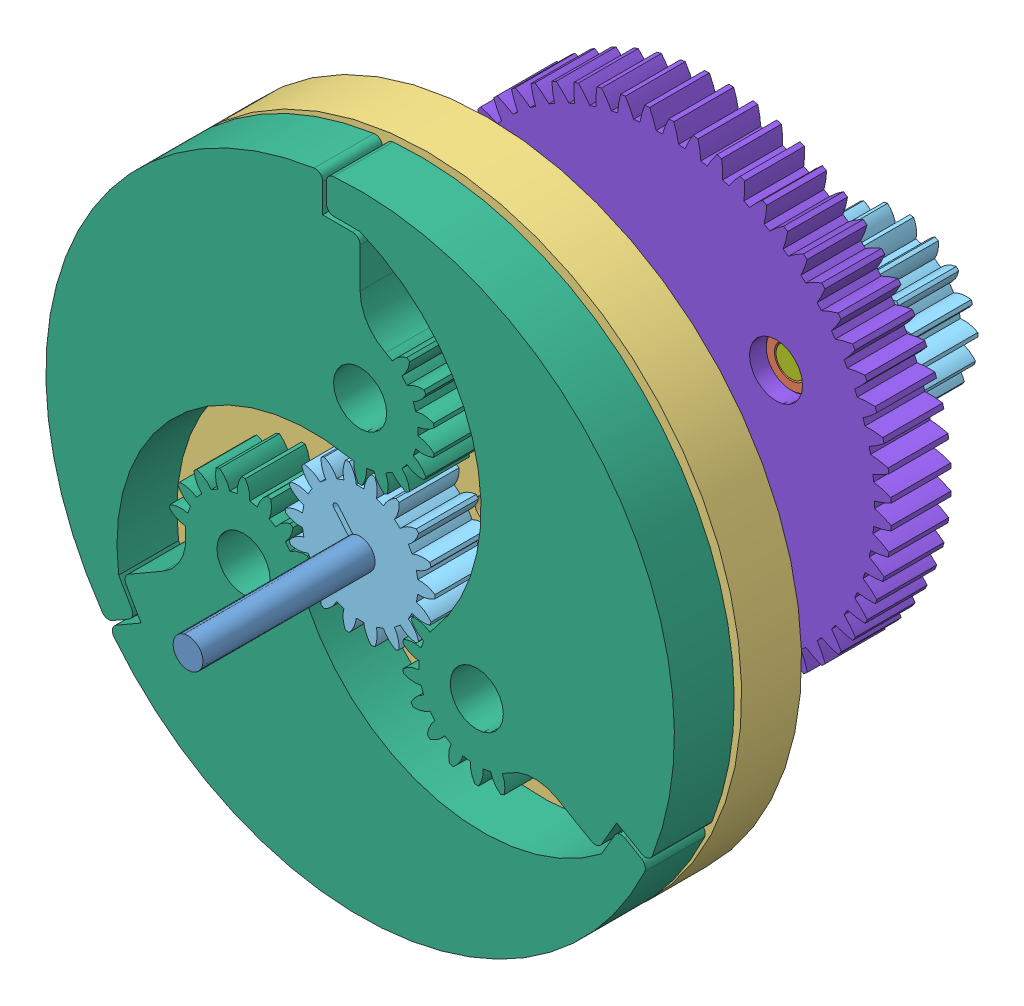
SolidWorks assembly GearSet2, configuration Default. Lengths in mm.
Overall size (98.99 105.75 80).
30 component instances, 9 part files, 45 mates.
Components (placement in the parent):
- Shaft4x55-1: Shaft4x55 [Default] at (30.5179 39.8122 29.3987) size (4 4 80)
- Bearing4x7x2.5-1: Bearing4x7x2.5 [Default] at (30.5179 39.8122 43.8987) x (0.886811 0.462132 0) z (0 0 1) size (7 7 2.5)
- Bearing4x7x2.5-2: Bearing4x7x2.5 [Default] at (30.5179 39.8122 38.3987) x (0.973436 0.22896 0) z (0 0 1) size (7 7 2.5)
- WheelHolder-1: WheelHolder [Default] at (30.5179 39.8122 69.3987) x (1 0 0) z (0 -1 0) size (84 11 84)
- Gear 1M 30T D7 Holder-Assem-1: Gear 1M 30T D7 Holder-Assem [Default] at (30.5179 39.8122 58.3987) x (0 0 1) z (1 0 0) size (8 31.88 32)
- Bearing4x7x2.5-3: Bearing4x7x2.5 [Default] at (30.5179 39.8122 74.8987) size (7 7 2.5)
- Bearing4x7x2.5-4: Bearing4x7x2.5 [Default] at (30.5179 39.8122 63.8987) size (7 7 2.5)
- Bearing4x7x2.5-5: Bearing4x7x2.5 [Default] at (30.5179 39.8122 58.3987) size (7 7 2.5)
- Bearing4x7x2.5-6: Bearing4x7x2.5 [Default] at (30.5179 39.8122 69.3987) size (7 7 2.5)
- Bearing4x7x2.5-7: Bearing4x7x2.5 [Default] at (30.5179 39.8122 47.3987) x (0.886811 0.462132 0) z (0 0 1) size (7 7 2.5)
- Bearing4x7x2.5-8: Bearing4x7x2.5 [Default] at (30.5179 39.8122 54.8987) x (0.886811 0.462132 0) z (0 0 1) size (7 7 2.5)
- Gear 1M 18T D4-Assem-3: Gear 1M 18T D4-Assem [Default] at (30.5179 39.8122 37.3987) x (0 0 -1) z (0.766439 0.642317 0) size (8 19.78 20)
- WheelClawPrinted-1: WheelClawPrinted [Default] at (30.5179 39.8122 68.3987) x (-0.5 0.866025 0) z (0.866025 0.5 0) size (51.89 8 66.01)
- WheelClawPrinted-2: WheelClawPrinted [Default] at (30.5179 39.8122 68.3987) x (-0.5 -0.866025 0) z (-0.866025 0.5 0) size (51.89 8 66.01)
- WheelClawPrinted-3: WheelClawPrinted [Default] at (30.5179 39.8122 68.3987) x (1 0 0) z (0 -1 0) size (51.89 8 66.01)
- Bearing4x7x2.5-9: Bearing4x7x2.5 [Default] at (46.1002 48.8228 41.8987) size (7 7 2.5)
- Shaft4x15-1: Shaft4x15 [Default] at (46.1002 48.8228 44.3987) x (0.934634 0.35561 0) z (0 0 -1) size (4 4 15)
- Bearing4x7x2.5-10: Bearing4x7x2.5 [Default] at (46.1002 48.8228 39.3987) size (7 7 2.5)
- Gear 1M 18T D4-Assem-6: Gear 1M 18T D4-Assem [Default] at (30.5179 39.8122 86.3987) x (0 0 -1) z (0.766439 0.642317 0) size (8 19.78 20)
- Gear 1M 60T D7 Holder-Assem-1: Gear 1M 60T D7 Holder-Assem [Default] at (30.5179 39.8122 38.3987) x (0 0 1) z (1 0.00068 0) size (8 61.95 61.95)
- Gear 1M 18T D4-Assem-7: Gear 1M 18T D4-Assem [Default] at (46.1002 48.8228 37.3987) x (0 0 -1) z (0.114199 0.993458 0) size (8 19.78 20)
- Bearing4x7x2.5-15: Bearing4x7x2.5 [Default] at (14.9233 48.8016 41.8987) x (-0.5 0.866025 0) z (0 0 1) size (7 7 2.5)
- Bearing4x7x2.5-16: Bearing4x7x2.5 [Default] at (30.5301 21.8122 41.8987) x (-0.5 -0.866025 0) z (0 0 1) size (7 7 2.5)
- Shaft4x15-4: Shaft4x15 [Default] at (14.9233 48.8016 44.3987) x (-0.775285 0.631612 0) z (0 0 -1) size (4 4 15)
- Shaft4x15-5: Shaft4x15 [Default] at (30.5301 21.8122 44.3987) x (-0.15935 -0.987222 0) z (0 0 -1) size (4 4 15)
- Bearing4x7x2.5-17: Bearing4x7x2.5 [Default] at (14.9233 48.8016 39.3987) x (-0.5 0.866025 0) z (0 0 1) size (7 7 2.5)
- Bearing4x7x2.5-18: Bearing4x7x2.5 [Default] at (30.5301 21.8122 39.3987) x (-0.5 -0.866025 0) z (0 0 1) size (7 7 2.5)
- Gear 1M 18T D4-Assem-8: Gear 1M 18T D4-Assem [Default] at (14.9233 48.8016 37.3987) x (0 0 -1) z (-0.917459 -0.39783 0) size (8 19.78 20)
- Gear 1M 18T D4-Assem-9: Gear 1M 18T D4-Assem [Default] at (30.5301 21.8122 37.3987) x (0 0 -1) z (0.80326 -0.595628 0) size (8 19.78 20)
- WheelHolder-Out-1: WheelHolder-Out [Default] at (30.5179 39.8122 95.3987) x (-1 0 0) z (0 -1 0) size (84 26 84) (hidden)
Mates (geometry in assembly coordinates):
- Concentric3: concentric aligned: cylinder of Shaft4x55-1 through (30.5179 39.8122 109.3987) axis (0 0 -1) radius 2; cylinder of Bearing4x7x2.5-1 through (30.5179 39.8122 46.3987) axis (0 0 -1) radius 2
- Concentric5: concentric aligned: cylinder of WheelHolder-1 through (30.5179 39.8122 77.3987) axis (0 0 -1) radius 3.55; cylinder of Bearing4x7x2.5-3 through (30.5179 39.8122 77.3987) axis (0 0 -1) radius 3.5
- Coincident4: coincident aligned: plane of WheelHolder-1 through (30.5179 39.8122 77.3987) normal (0 0 1); plane of Bearing4x7x2.5-3 through (30.5179 39.8122 77.3987) normal (0 0 1)
- Concentric6: concentric aligned: cylinder of WheelHolder-1 through (30.5179 39.8122 77.3987) axis (0 0 -1) radius 3.55; cylinder of Bearing4x7x2.5-6 through (30.5179 39.8122 71.8987) axis (0 0 -1) radius 3.5
- Coincident5: coincident aligned: plane of WheelHolder-1 through (30.5179 39.8122 69.3987) normal (0 0 -1); plane of Bearing4x7x2.5-6 through (30.5179 39.8122 69.3987) normal (0 0 -1)
- Concentric7: concentric aligned: cylinder of Gear 1M 30T D7 Holder-Assem-1 through (30.5179 39.8122 108.3987) axis (0 0 -1) radius 3.5; cylinder of Bearing4x7x2.5-5 through (30.5179 39.8122 60.8987) axis (0 0 -1) radius 3.5
- Coincident6: coincident aligned: plane of Gear 1M 30T D7 Holder-Assem-1 through (30.5179 39.8122 58.3987) normal (0 0 -1); plane of Bearing4x7x2.5-5 through (30.5179 39.8122 58.3987) normal (0 0 -1)
- Concentric8: concentric aligned: cylinder of Gear 1M 30T D7 Holder-Assem-1 through (30.5179 39.8122 108.3987) axis (0 0 -1) radius 3.5; cylinder of Bearing4x7x2.5-4 through (30.5179 39.8122 66.3987) axis (0 0 -1) radius 3.5
- Coincident7: coincident aligned: plane of Gear 1M 30T D7 Holder-Assem-1 through (30.5179 39.8122 66.3987) normal (0 0 1); plane of Bearing4x7x2.5-4 through (30.5179 39.8122 66.3987) normal (0 0 1)
- Concentric9: concentric aligned: cylinder of Shaft4x55-1 through (30.5179 39.8122 109.3987) axis (0 0 -1) radius 2; cylinder of Bearing4x7x2.5-4 through (30.5179 39.8122 66.3987) axis (0 0 -1) radius 2
- Concentric10: concentric aligned: cylinder of Shaft4x55-1 through (30.5179 39.8122 109.3987) axis (0 0 -1) radius 2; cylinder of Bearing4x7x2.5-3 through (30.5179 39.8122 77.3987) axis (0 0 -1) radius 2
- Concentric11: concentric anti-aligned: cylinder of WheelHolder-1 through (22.7236 44.3122 77.3987) axis (0 0 -1) radius 1.45; cylinder of Gear 1M 30T D7 Holder-Assem-1 through (22.7236 44.3122 56.3987) axis (0 0 1) radius 1.55
- Concentric14: concentric aligned: cylinder of Shaft4x55-1 through (30.5179 39.8122 109.3987) axis (0 0 -1) radius 2; cylinder of Bearing4x7x2.5-8 through (30.5179 39.8122 57.3987) axis (0 0 -1) radius 2
- Concentric15: concentric aligned: cylinder of Shaft4x55-1 through (30.5179 39.8122 109.3987) axis (0 0 -1) radius 2; cylinder of Bearing4x7x2.5-7 through (30.5179 39.8122 49.8987) axis (0 0 -1) radius 2
- Distance3: distance = 10 mm anti-aligned: plane of Bearing4x7x2.5-7 through (30.5179 39.8122 47.3987) normal (0 0 -1); plane of Bearing4x7x2.5-8 through (30.5179 39.8122 57.3987) normal (0 0 1)
- Distance4: distance = 1 mm anti-aligned: plane of Bearing4x7x2.5-7 through (30.5179 39.8122 47.3987) normal (0 0 -1); plane of Bearing4x7x2.5-1 through (30.5179 39.8122 46.3987) normal (0 0 1)
- Distance5: distance = 1 mm anti-aligned: plane of Bearing4x7x2.5-5 through (30.5179 39.8122 58.3987) normal (0 0 -1); plane of Bearing4x7x2.5-8 through (30.5179 39.8122 57.3987) normal (0 0 1)
- Concentric20: concentric anti-aligned: cylinder of Shaft4x55-1 through (30.5179 39.8122 109.3987) axis (0 0 -1) radius 2; cylinder of Gear 1M 18T D4-Assem-3 through (30.5179 39.8122 -12.6014) axis (0 0 1) radius 2
- Coincident11: coincident aligned: plane of Shaft4x55-1 through (30.5179 39.8122 29.3987) normal (0 0 -1); plane of Gear 1M 18T D4-Assem-3 through (30.5179 39.8122 29.3987) normal (0 0 -1)
- Distance9: distance = 1 mm anti-aligned: plane of WheelClawPrinted-1 through (14.9294 30.8122 78.3987) normal (0 0 -1); plane of WheelHolder-1 through (30.5179 39.8122 77.3987) normal (0 0 1)
- Concentric24: concentric anti-aligned: cylinder of Bearing4x7x2.5-9 through (46.1002 48.8228 44.3987) axis (0 0 -1) radius 2; cylinder of Shaft4x15-1 through (46.1002 48.8228 29.3987) axis (0 0 1) radius 2
- Concentric25: concentric anti-aligned: cylinder of Shaft4x15-1 through (46.1002 48.8228 29.3987) axis (0 0 1) radius 2; cylinder of Bearing4x7x2.5-10 through (46.1002 48.8228 41.8987) axis (0 0 -1) radius 2
- Coincident17: coincident aligned: plane of Bearing4x7x2.5-9 through (46.1002 48.8228 44.3987) normal (0 0 1); plane of Shaft4x15-1 through (46.1002 48.8228 44.3987) normal (0 0 1)
- Coincident18: coincident anti-aligned: plane of Bearing4x7x2.5-9 through (46.1002 48.8228 41.8987) normal (0 0 -1); plane of Bearing4x7x2.5-10 through (46.1002 48.8228 41.8987) normal (0 0 1)
- Concentric26: concentric anti-aligned: cylinder of Shaft4x55-1 through (30.5179 39.8122 109.3987) axis (0 0 -1) radius 2; cylinder of Gear 1M 18T D4-Assem-6 through (30.5179 39.8122 36.3986) axis (0 0 1) radius 2
- Concentric28: concentric aligned: cylinder of Bearing4x7x2.5-1 through (30.5179 39.8122 46.3987) axis (0 0 -1) radius 3.5; cylinder of Gear 1M 60T D7 Holder-Assem-1 through (30.5179 39.8122 88.3987) axis (0 0 -1) radius 3.55
- Coincident20: coincident aligned: plane of Bearing4x7x2.5-1 through (30.5179 39.8122 46.3987) normal (0 0 1); plane of Gear 1M 60T D7 Holder-Assem-1 through (30.5179 39.8122 46.3987) normal (0 0 1)
- Coincident21: coincident aligned: plane of Bearing4x7x2.5-2 through (30.5179 39.8122 38.3987) normal (0 0 -1); plane of Gear 1M 60T D7 Holder-Assem-1 through (30.5179 39.8122 38.3987) normal (0 0 -1)
- Concentric29: concentric aligned: cylinder of Shaft4x55-1 through (30.5179 39.8122 109.3987) axis (0 0 -1) radius 2; cylinder of Bearing4x7x2.5-2 through (30.5179 39.8122 40.8987) axis (0 0 -1) radius 3.5
- Distance10: distance = 1 mm anti-aligned: plane of Gear 1M 60T D7 Holder-Assem-1 through (30.5179 39.8122 38.3987) normal (0 0 -1); plane of Gear 1M 18T D4-Assem-3 through (30.5179 39.8122 37.3987) normal (0 0 1)
- Concentric30: concentric anti-aligned: cylinder of Bearing4x7x2.5-10 through (46.1002 48.8228 41.8987) axis (0 0 -1) radius 3.5; cylinder of Gear 1M 60T D7 Holder-Assem-1 through (46.1002 48.8228 36.3987) axis (0 0 1) radius 3.55
- Coincident23: coincident anti-aligned: cylinder of Shaft4x15-1 through (46.1002 48.8228 29.3987) axis (0 0 1) radius 2; circle of Gear 1M 18T D4-Assem-7
- Coincident24: coincident aligned: plane of Shaft4x15-1 through (46.1002 48.8228 29.3987) normal (0 0 -1); plane of Gear 1M 18T D4-Assem-7 through (46.1002 48.8228 29.3987) normal (0 0 -1)
- Distance11: distance = 1 mm aligned: plane of Gear 1M 60T D7 Holder-Assem-1 through (30.5179 39.8122 38.3987) normal (0 0 -1); plane of Bearing4x7x2.5-10 through (46.1002 48.8228 39.3987) normal (0 0 -1)
- Coincident26: coincident aligned: plane of Gear 1M 18T D4-Assem-3 through (27.6128 43.9013 39.3987) normal (-0.766439 -0.642317 0); plane of Gear 1M 18T D4-Assem-6 through (27.6128 43.9013 88.3987) normal (-0.766439 -0.642317 0)
- GearMate2: gear = 20 : 20 mm: cylinder of Gear 1M 18T D4-Assem-7 through (46.1002 48.8228 47.3987) axis (0 0 1) radius 10; cylinder of Gear 1M 18T D4-Assem-3 through (30.5179 39.8122 47.3987) axis (0 0 1) radius 10
- Concentric32: concentric aligned: cylinder of WheelHolder-1 through (30.5179 57.8122 77.3987) axis (0 0 -1) radius 1.95; cylinder of WheelClawPrinted-3 through (30.5179 57.8122 86.3987) axis (0 0 -1) radius 3.55
- Parallel1: parallel anti-aligned: plane of Gear 1M 30T D7 Holder-Assem-1 through (31.0179 45.8122 68.3987) normal (-1 0 0)
- Coincident28: coincident anti-aligned: plane of WheelHolder-1 through (30.5179 39.8122 66.3987) normal (0 0 -1); plane of Gear 1M 30T D7 Holder-Assem-1 through (30.5179 39.8122 66.3987) normal (0 0 1)
- Concentric35: concentric anti-aligned: cylinder of WheelHolder-1 through (30.5179 39.8122 77.3987) axis (0 0 -1) radius 42; cylinder of WheelHolder-Out-1 through (30.5179 39.8122 87.3987) axis (0 0 1) radius 42
- Coincident35: coincident aligned: plane of WheelHolder-1 through (31.0179 46.8122 67.3987) normal (-1 0 0); plane of WheelHolder-Out-1 through (31.0179 45.8122 97.3987) normal (-1 0 0)
- Coincident37: coincident anti-aligned: plane of WheelHolder-1 through (30.5179 39.8122 77.3987) normal (0 0 1); plane of WheelHolder-Out-1 through (26.9269 15.5925 77.3987) normal (0 0 -1)
- GearMate3: gear = 20 : 20 mm: cylinder of WheelClawPrinted-1 through (14.9294 30.8122 86.3987) axis (0 0 -1) radius 10; cylinder of Gear 1M 18T D4-Assem-6 through (30.5179 39.8122 96.3987) axis (0 0 1) radius 10
- Coincident38: coincident aligned: plane of WheelClawPrinted-1 through (14.9294 30.8122 78.3987) normal (0 0 -1); plane of Gear 1M 18T D4-Assem-6 through (30.5179 39.8122 78.3987) normal (0 0 -1)
- LimitAngle3: limit planar angle = 2.094395 rad anti-aligned: plane of WheelClawPrinted-1 through (-1.2664 21.4615 86.3987) normal (-0.5 0.866025 0); plane of WheelHolder-Out-1 through (14.9294 42.8122 77.3987) normal (-1 0 0)
